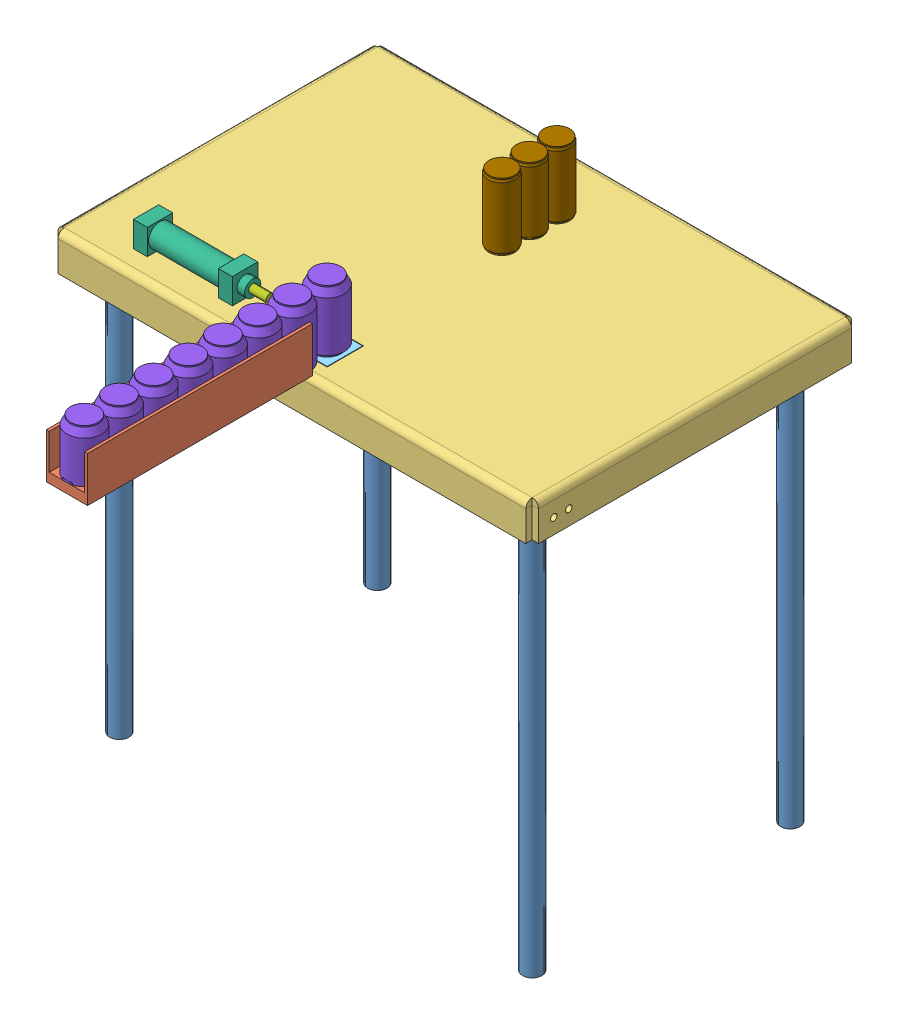
SolidWorks assembly Full_Assembly_v6, configuration Default. Lengths in mm.
Overall size (946.15 1042.06 1084.08).
23 component instances, 12 part files, 63 mates.
Components (placement in the parent):
- M37 Metal Table-1: M37 Metal Table [Default] at (-122.75 340.8931 1031.9817) size (914.4 863.6 609.6)
- Goose Output-1: Goose Output [Default] at (293.9688 417.0931 1047.8567) size (80.96 88.9 442.73)
- Table Topper-1: Table Topper [Default] at (-125.925 340.8931 1035.1567) size (946.15 72.1 641.35)
- Load Cell Assembly-1: Load Cell Assembly [Default] at (309.0555 358.077 899.7114) size (69.85 23.2 103.99)
  - Load Cell and Brace-1: Load Cell and Brace [Default] at (-9.1055 31.7162 92.7424) size (69 14.2 83)
  - scalePlate_v2_234-1: scalePlate_v2_234 [Default] at (-9.5305 54.9162 113.7283) x (0 0 -1) z (-1 0 0) size (69.85 9 69.85)
- Cylinder-1: Cylinder [Default] at (-22.0508 462.9931 953.5147) x (0 0 1) z (1 0 0) size (50 50 210)
- Rod-1: Rod [Default] at (221.9492 437.9931 978.5147) x (0 0.637822 -0.770184) z (0 0.770184 0.637822) size (16 134 16)
- can355mL-1: can355mL [Default] at (334.45 412.9931 1115.1477) x (0 0 -1) z (1 0 0) size (68.26 122.24 68.26)
- can355mL-2: can355mL [Default] at (334.45 412.9931 1251.6727) x (0 0 -1) z (1 0 0) size (68.26 122.24 68.26)
- can355mL-3: can355mL [Default] at (334.45 412.9931 1183.4102) x (0 0 -1) z (1 0 0) size (68.26 122.24 68.26)
- can250mL-1: can250mL [Default] at (334.45 412.9931 634.4892) x (0.234731 0 0.97206) z (-0.97206 0 0.234731) size (53.98 131.76 53.98)
- can250mL-2: can250mL [Default] at (334.45 412.9931 580.5142) x (0.907124 0 -0.420864) z (0.420864 0 0.907124) size (53.98 131.76 53.98)
- can250mL-3: can250mL [Default] at (334.45 412.9931 526.5392) x (0.515444 0 0.856923) z (-0.856923 0 0.515444) size (53.98 131.76 53.98)
- can355mL-7: can355mL [Default] at (334.45 412.9931 1046.8852) x (0 0 -1) z (1 0 0) size (68.26 122.24 68.26)
- can355mL-8: can355mL [Default] at (334.45 412.9931 1456.4602) x (0 0 -1) z (1 0 0) size (68.26 122.24 68.26)
- can355mL-9: can355mL [Default] at (334.45 412.9931 1319.9352) x (0 0 -1) z (1 0 0) size (68.26 122.24 68.26)
- can355mL-10: can355mL [Default] at (334.45 412.9931 1388.1977) x (0 0 -1) z (1 0 0) size (68.26 122.24 68.26)
- can355mL-11: can355mL [Default] at (334.45 412.9931 978.6227) x (0 0 -1) z (1 0 0) size (68.26 122.24 68.26)
- AmpCase_Assembly_v1-1: AmpCase_Assembly_v1 [Default] at (378.0256 441.5889 898.6464) x (0 0 -1) z (-1 0 0) size (83 107 59)
  - AmpCase_LID_83x59x33_v1-1: AmpCase_LID_83x59x33_v1 [Default] at (42.2994 148.2958 -6.3457) x (1 0 0) z (0 0 -1) size (83 7 59)
  - AmpCase83x59x33_v1-1: AmpCase83x59x33_v1 [Default] at (42.2994 41.2958 52.6543) size (83 26 59)
- Solenoid_v1-1: Solenoid_v1 [Default] at (452.5858 378.2931 857.7853) size (118 22 83)
Mates (geometry in assembly coordinates):
- Width1: width aligned: plane of M37 Metal Table-1 through (791.65 366.2931 1031.9817) normal (1 0 0); plane of M37 Metal Table-1 through (-122.75 366.2931 1031.9817) normal (-1 0 0); plane of Table Topper-1 through (807.525 400.2931 1035.1567) normal (1 0 0); plane of Table Topper-1 through (-138.625 400.2931 1035.1567) normal (-1 0 0)
- Width2: width aligned: plane of M37 Metal Table-1 through (-122.75 366.2931 1031.9817) normal (0 0 1); plane of M37 Metal Table-1 through (-122.75 366.2931 422.3817) normal (0 0 -1); plane of Table Topper-1 through (-125.925 400.2931 1047.8567) normal (0 0 1); plane of Table Topper-1 through (-125.925 400.2931 406.5067) normal (0 0 -1)
- Distance1: distance = 863.6 mm aligned: plane of M37 Metal Table-1 through (-122.75 -446.5069 1031.9817) normal (0 -1 0); plane of Goose Output-1 through (374.9313 417.0931 1490.5914) normal (0 -1 0)
- LimitDistance1: limit distance = 432.5938 mm aligned: plane of Goose Output-1 through (374.9313 505.9931 1490.5914) normal (1 0 0); plane of Table Topper-1 through (807.525 400.2931 1035.1567) normal (1 0 0)
- LimitDistance2: limit distance = 432.5938 mm aligned: plane of Table Topper-1 through (-138.625 400.2931 1035.1567) normal (-1 0 0); plane of Goose Output-1 through (293.9688 417.0931 1490.5914) normal (-1 0 0)
- Parallel1: parallel aligned: plane of Goose Output-1 through (299.525 436.1431 1490.5914) normal (0 1 0); plane of Table Topper-1 through (-125.925 412.9931 1035.1567) normal (0 1 0)
- Coincident7: coincident aligned: plane of Table Topper-1 through (-125.925 412.9931 1035.1567) normal (0 1 0); plane of Load Cell Assembly-1/scalePlate_v2_234-1 through (299.525 412.9931 1013.4397) normal (0 1 0)
- Concentric1: concentric anti-aligned: cylinder of Cylinder-1 through (187.9492 437.9931 978.5147) axis (-1 0 0) radius 16; cylinder of Rod-1 through (87.9492 437.9931 978.5147) axis (1 0 0) radius 8
- LimitDistance3: limit distance = 34 mm aligned: plane of Rod-1 through (221.9492 437.9931 978.5147) normal (1 0 0); plane of Cylinder-1 through (187.9492 437.9931 978.5147) normal (1 0 0)
- Parallel2: parallel anti-aligned: plane of Table Topper-1 through (-125.925 400.2931 1047.8567) normal (0 0 1); plane of Cylinder-1 through (172.9492 462.9931 953.5147) normal (0 0 -1)
- Coincident9: coincident anti-aligned: plane of Table Topper-1 through (-125.925 412.9931 1035.1567) normal (0 1 0); plane of Cylinder-1 through (5.4492 412.9931 953.5147) normal (0 -1 0)
- Width3: width anti-aligned: plane of Goose Output-1 through (374.9313 505.9931 1490.5914) normal (1 0 0); plane of Goose Output-1 through (293.9688 417.0931 1490.5914) normal (-1 0 0); plane of Load Cell Assembly-1/scalePlate_v2_234-1 through (299.525 408.9931 1013.4397) normal (-1 0 0); plane of Load Cell Assembly-1/scalePlate_v2_234-1 through (369.375 408.9931 1013.4397) normal (1 0 0)
- Width4: width anti-aligned: plane of Cylinder-1 through (172.9492 462.9931 953.5147) normal (0 0 -1); plane of Cylinder-1 through (172.9492 462.9931 1003.5147) normal (0 0 1); plane of Load Cell Assembly-1/scalePlate_v2_234-1 through (299.525 408.9931 1013.4397) normal (0 0 1); plane of Load Cell Assembly-1/scalePlate_v2_234-1 through (299.525 408.9931 943.5897) normal (0 0 -1)
- Width5: width anti-aligned: plane of Table Topper-1 through (807.525 400.2931 1035.1567) normal (1 0 0); plane of Table Topper-1 through (-138.625 400.2931 1035.1567) normal (-1 0 0); plane of Load Cell Assembly-1/scalePlate_v2_234-1 through (299.525 408.9931 1013.4397) normal (-1 0 0); plane of Load Cell Assembly-1/scalePlate_v2_234-1 through (369.375 408.9931 1013.4397) normal (1 0 0)
- Coincident11: coincident anti-aligned: plane of Table Topper-1 through (-125.925 412.9931 1035.1567) normal (0 1 0); plane of can250mL-1 through (340.4122 412.9931 659.1796) normal (0 -1 0)
- Coincident18: coincident anti-aligned: plane of Table Topper-1 through (-125.925 412.9931 1035.1567) normal (0 1 0); plane of can355mL-2 through (334.45 412.9931 1224.6852) normal (0 -1 0)
- Coincident19: coincident anti-aligned: plane of Table Topper-1 through (-125.925 412.9931 1035.1567) normal (0 1 0); plane of can355mL-3 through (334.45 412.9931 1156.4227) normal (0 -1 0)
- Tangent5: tangent anti-aligned: cylinder of can355mL-2 through (334.45 412.9931 1251.6727) axis (0 -1 0) radius 34.1313; cylinder of can355mL-3 through (334.45 412.9931 1183.4102) axis (0 -1 0) radius 34.1313
- Width6: width: plane of Goose Output-1 through (299.525 505.9931 1490.5914) normal (1 0 0); plane of Goose Output-1 through (369.375 436.1431 1490.5914) normal (-1 0 0); cylinder of can250mL-1 through (334.45 412.9931 634.4892) axis (0 -1 0) radius 26.9875
- Width8: width: plane of Goose Output-1 through (369.375 436.1431 1490.5914) normal (-1 0 0); plane of Goose Output-1 through (299.525 505.9931 1490.5914) normal (1 0 0); cylinder of can355mL-2 through (334.45 412.9931 1251.6727) axis (0 -1 0) radius 34.1313
- Width10: width: plane of Goose Output-1 through (299.525 505.9931 1490.5914) normal (1 0 0); plane of Goose Output-1 through (369.375 436.1431 1490.5914) normal (-1 0 0); cylinder of can355mL-3 through (334.45 412.9931 1183.4102) axis (0 -1 0) radius 34.1313
- Coincident20: coincident anti-aligned: plane of Table Topper-1 through (-125.925 412.9931 1035.1567) normal (0 1 0); plane of can250mL-2 through (357.491 412.9931 569.8243) normal (0 -1 0)
- Coincident21: coincident anti-aligned: plane of Table Topper-1 through (-125.925 412.9931 1035.1567) normal (0 1 0); plane of can250mL-3 through (347.5423 412.9931 548.3051) normal (0 -1 0)
- Tangent6: tangent anti-aligned: cylinder of can250mL-1 through (334.45 412.9931 634.4892) axis (0 -1 0) radius 26.9875; cylinder of can250mL-2 through (334.45 412.9931 580.5142) axis (0 -1 0) radius 26.9875
- Tangent7: tangent anti-aligned: cylinder of can250mL-2 through (334.45 412.9931 580.5142) axis (0 -1 0) radius 26.9875; cylinder of can250mL-3 through (334.45 412.9931 526.5392) axis (0 -1 0) radius 26.9875
- Width11: width: plane of Goose Output-1 through (299.525 505.9931 1490.5914) normal (1 0 0); plane of Goose Output-1 through (369.375 436.1431 1490.5914) normal (-1 0 0); cylinder of can250mL-2 through (334.45 412.9931 580.5142) axis (0 -1 0) radius 26.9875
- Width12: width: plane of Goose Output-1 through (299.525 505.9931 1490.5914) normal (1 0 0); plane of Goose Output-1 through (369.375 436.1431 1490.5914) normal (-1 0 0); cylinder of can250mL-3 through (334.45 412.9931 526.5392) axis (0 -1 0) radius 26.9875
- Coincident22: coincident anti-aligned: plane of Goose Output-1 through (293.9688 417.0931 1047.8567) normal (0 0 -1); plane of Table Topper-1 through (-125.925 400.2931 1047.8567) normal (0 0 1)
- Width14: width aligned: plane of Table Topper-1 through (370.391 340.8931 1014.4557) normal (-1 0 0); plane of Load Cell Assembly-1/scalePlate_v2_234-1 through (298.509 340.8931 1014.4557) normal (1 0 0); plane of Table Topper-1 through (299.525 408.9931 1013.4397) normal (-1 0 0); plane of Load Cell Assembly-1/scalePlate_v2_234-1 through (369.375 408.9931 1013.4397) normal (1 0 0)
- Width15: width anti-aligned: plane of Table Topper-1 through (298.509 340.8931 1014.4557) normal (0 0 -1); plane of Load Cell Assembly-1/scalePlate_v2_234-1 through (298.509 340.8931 942.5737) normal (0 0 1); plane of Table Topper-1 through (299.525 408.9931 1013.4397) normal (0 0 1); plane of Load Cell Assembly-1/scalePlate_v2_234-1 through (299.525 408.9931 943.5897) normal (0 0 -1)
- Width17: width: plane of Goose Output-1 through (369.375 436.1431 1490.5914) normal (-1 0 0); plane of can355mL-4 through (299.525 505.9931 1490.5914) normal (1 0 0); cylinder of Goose Output-1 through (334.45 436.1431 1259.8293) axis (0 -1 0) radius 34.1313
- Coincident31: coincident anti-aligned: plane of Table Topper-1 through (-125.925 412.9931 1035.1567) normal (0 1 0); plane of can355mL-7 through (334.45 412.9931 1019.8977) normal (0 -1 0)
- Width19: width: plane of Goose Output-1 through (369.375 436.1431 1490.5914) normal (-1 0 0); plane of can355mL-7 through (299.525 505.9931 1490.5914) normal (1 0 0); cylinder of Goose Output-1 through (334.45 412.9931 1046.8852) axis (0 -1 0) radius 34.1313
- Coincident33: coincident anti-aligned: plane of Table Topper-1 through (-125.925 412.9931 1035.1567) normal (0 1 0); plane of can355mL-1 through (334.45 412.9931 1088.1602) normal (0 -1 0)
- Tangent13: tangent anti-aligned: cylinder of can355mL-1 through (334.45 412.9931 1115.1477) axis (0 -1 0) radius 34.1313; cylinder of can355mL-3 through (334.45 412.9931 1183.4102) axis (0 -1 0) radius 34.1313
- Width20: width: plane of Goose Output-1 through (299.525 505.9931 1490.5914) normal (1 0 0); plane of can355mL-1 through (369.375 436.1431 1490.5914) normal (-1 0 0); cylinder of Goose Output-1 through (334.45 412.9931 1115.1477) axis (0 -1 0) radius 34.1313
- Parallel4: parallel aligned: plane of M37 Metal Table-1 through (-122.75 366.2931 1031.9817) normal (0 0 1); plane of can355mL-7 through (334.45 412.9931 1081.0164) normal (0 0 1)
- Parallel5: parallel aligned: plane of M37 Metal Table-1 through (-122.75 366.2931 1031.9817) normal (0 0 1); plane of can355mL-2 through (334.45 412.9931 1285.8039) normal (0 0 1)
- Parallel6: parallel aligned: plane of M37 Metal Table-1 through (-122.75 366.2931 1031.9817) normal (0 0 1); plane of can355mL-3 through (334.45 412.9931 1217.5414) normal (0 0 1)
- Parallel7: parallel aligned: plane of M37 Metal Table-1 through (-122.75 366.2931 1031.9817) normal (0 0 1); plane of can355mL-1 through (334.45 412.9931 1149.2789) normal (0 0 1)
- LimitDistance14: limit distance = 68.2625 mm aligned: plane of can355mL-7 through (334.45 412.9931 1081.0164) normal (0 0 1); plane of can355mL-1 through (334.45 412.9931 1149.2789) normal (0 0 1)
- Tangent14: tangent anti-aligned: cylinder of can355mL-9 through (334.45 412.9931 1319.9352) axis (0 -1 0) radius 34.1313; cylinder of can355mL-10 through (334.45 412.9931 1388.1977) axis (0 -1 0) radius 34.1313
- Tangent15: tangent anti-aligned: cylinder of can355mL-8 through (334.45 412.9931 1456.4602) axis (0 -1 0) radius 34.1313; cylinder of can355mL-10 through (334.45 412.9931 1388.1977) axis (0 -1 0) radius 34.1313
- Coincident38: coincident anti-aligned: plane of Table Topper-1 through (-125.925 412.9931 1035.1567) normal (0 1 0); plane of can355mL-8 through (334.45 412.9931 1429.4727) normal (0 -1 0)
- Coincident39: coincident aligned: plane of can355mL-9 through (334.45 412.9931 1292.9477) normal (0 -1 0); plane of can355mL-10 through (334.45 412.9931 1361.2102) normal (0 -1 0)
- Coincident40: coincident anti-aligned: plane of Table Topper-1 through (-125.925 412.9931 1035.1567) normal (0 1 0); plane of can355mL-10 through (334.45 412.9931 1361.2102) normal (0 -1 0)
- Width21: width: plane of Goose Output-1 through (299.525 505.9931 1490.5914) normal (1 0 0); plane of Goose Output-1 through (369.375 436.1431 1490.5914) normal (-1 0 0); cylinder of can355mL-8 through (334.45 412.9931 1456.4602) axis (0 -1 0) radius 34.1313
- Width22: width: plane of Goose Output-1 through (374.9313 505.9931 1490.5914) normal (1 0 0); plane of Goose Output-1 through (293.9688 417.0931 1490.5914) normal (-1 0 0); cylinder of can355mL-10 through (334.45 412.9931 1388.1977) axis (0 -1 0) radius 34.1313
- Width23: width: plane of Goose Output-1 through (374.9313 505.9931 1490.5914) normal (1 0 0); plane of Goose Output-1 through (293.9688 417.0931 1490.5914) normal (-1 0 0); cylinder of can355mL-9 through (334.45 412.9931 1319.9352) axis (0 -1 0) radius 34.1313
- LimitDistance15: limit distance = 68.2625 mm aligned: plane of can355mL-9 through (334.45 412.9931 1354.0664) normal (0 0 1); plane of can355mL-2 through (334.45 412.9931 1285.8039) normal (0 0 1)
- Parallel8: parallel aligned: plane of M37 Metal Table-1 through (-122.75 366.2931 1031.9817) normal (0 0 1); plane of can355mL-8 through (334.45 412.9931 1490.5914) normal (0 0 1)
- Parallel10: parallel aligned: plane of M37 Metal Table-1 through (-122.75 366.2931 1031.9817) normal (0 0 1); plane of can355mL-10 through (334.45 412.9931 1422.3289) normal (0 0 1)
- LimitDistance16: limit distance = 0 mm aligned: plane of can355mL-8 through (334.45 412.9931 1490.5914) normal (0 0 1); plane of Goose Output-1 through (293.9688 417.0931 1490.5914) normal (0 0 1)
- Parallel12: parallel aligned: plane of M37 Metal Table-1 through (-122.75 366.2931 1031.9817) normal (0 0 1); plane of can355mL-11 through (334.45 412.9931 1012.7539) normal (0 0 1)
- LimitDistance18: limit distance = 68.2625 mm aligned: plane of can355mL-11 through (334.45 412.9931 1012.7539) normal (0 0 1); plane of can355mL-7 through (334.45 412.9931 1081.0164) normal (0 0 1)
- PathMate3: path: point of can355mL-11
- Parallel13: parallel anti-aligned: plane of Table Topper-1 through (-125.925 412.9931 1035.1567) normal (0 1 0); plane of can355mL-11 through (334.45 412.9931 951.6352) normal (0 -1 0)
- Parallel14: parallel aligned: plane of M37 Metal Table-1 through (-122.75 366.2931 1031.9817) normal (0 0 1); plane of can355mL-11 through (334.45 412.9931 1012.7539) normal (0 0 1)
- Coincident41: coincident aligned: plane of M37 Metal Table-1 through (-122.75 340.8931 1031.9817) normal (0 -1 0); plane of Table Topper-1 through (-125.925 340.8931 1035.1567) normal (0 -1 0)
- Coincident42: coincident anti-aligned: plane of Table Topper-1 through (-125.925 400.2931 1035.1567) normal (0 -1 0); plane of AmpCase_Assembly_v1-1/AmpCase83x59x33_v1-1 through (325.3712 400.2931 856.347) normal (0 1 0)
- Parallel15: parallel aligned: plane of M37 Metal Table-1 through (-122.75 366.2931 1031.9817) normal (0 0 1); plane of AmpCase_Assembly_v1-1/AmpCase83x59x33_v1-1 through (325.3712 397.2931 856.347) normal (0 0 1)
- Parallel16: parallel aligned: plane of M37 Metal Table-1 through (-122.75 366.2931 1031.9817) normal (0 0 1); plane of Solenoid_v1-1 through (452.5858 400.2931 857.7853) normal (0 0 1)
- Coincident45: coincident aligned: plane of AmpCase_Assembly_v1-1/AmpCase83x59x33_v1-1 through (325.3712 400.2931 856.347) normal (0 1 0); plane of Solenoid_v1-1 through (452.5858 400.2931 857.7853) normal (0 1 0)
